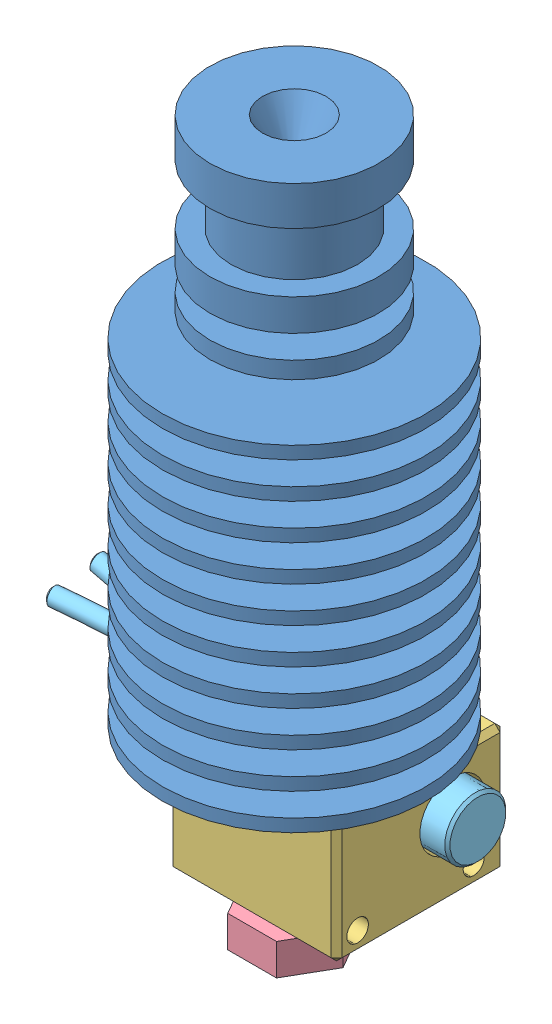
SolidWorks assembly E3D Hot End, configuration Default. Lengths in mm.
Overall size (41.43 69.7 25).
5 component instances, 5 part files, 13 mates.
Components (placement in the parent):
- Heat Sink^E3D Hot End-1: Heat Sink^E3D Hot End [Default] at (0 50.1 0) x (-1 0 0) z (0 0 1) size (25 50.1 25) (virtual)
- Heat Break^E3D Hot End-1: Heat Break^E3D Hot End [Default] at (0 18 0) x (-0.28377 0 0.958892) z (0.958892 0 0.28377) size (6 25.1 6) (virtual)
- Heater Block^E3D Hot End-1: Heater Block^E3D Hot End [Default] at (0 -7.85 -4) x (0 0 -1) z (1 0 0) size (16 12 16) (virtual)
- Nozzle^E3D Hot End-1: Nozzle^E3D Hot End [Default] at (0 -19.6 0) x (0.93034 0 0.366697) z (-0.366697 0 0.93034) size (8.59 12.5 9.14) (virtual)
- Heating Element^E3D Hot End-1: Heating Element^E3D Hot End [Default] at (-0.2277 -6.85 -7) x (1 0 0) z (0 0.127992 0.991775) size (39.33 5.8 6.45) (virtual)
Mates (geometry in assembly coordinates):
- Parallel1: parallel anti-aligned: plane of Heat Break^E3D Hot End-1 through (0 -7.1 0) normal (0 -1 0); plane of assembly through (0 0 0) normal (0 1 0)
- Coincident2: coincident: plane of Heat Sink^E3D Hot End-1 through (0 0 0) normal (0 -1 0); plane of assembly through (0 0 0) normal (0 1 0)
- Coincident3: coincident: plane of Heat Sink^E3D Hot End-1 through (0 50.1 0) normal (0 0 1); plane of assembly through (0 0 0) normal (0 0 1)
- Coincident4: coincident anti-aligned: plane of Heat Sink^E3D Hot End-1; plane of assembly through (0 0 0) normal (1 0 0)
- Concentric2: concentric aligned: cylinder of Heat Sink^E3D Hot End-1 through (0 0 0) axis (0 -1 0) radius 3; cylinder of Heat Break^E3D Hot End-1 through (0 -7.1 0) axis (0 -1 0) radius 3
- Coincident6: coincident anti-aligned: plane of Heat Sink^E3D Hot End-1 through (-1 18 0) normal (0 -1 0); plane of Heat Break^E3D Hot End-1 through (0 18 0) normal (0 1 0)
- Concentric3: concentric aligned: cylinder of Heat Break^E3D Hot End-1 through (0 -7.1 0) axis (0 -1 0) radius 3; cylinder of Heater Block^E3D Hot End-1 through (0 -1.85 0) axis (0 -1 0) radius 3
- Concentric4: concentric anti-aligned: cylinder of Heater Block^E3D Hot End-1 through (0 -1.85 0) axis (0 -1 0) radius 3; cylinder of Nozzle^E3D Hot End-1 through (0 -7.1 0) axis (0 1 0) radius 3
- Coincident7: coincident anti-aligned: plane of Heat Break^E3D Hot End-1 through (0 -7.1 0) normal (0 -1 0); plane of Nozzle^E3D Hot End-1 through (0 -7.1 0) normal (0 1 0)
- Tangent1: tangent: circle of Heat Break^E3D Hot End-1; circle of Heater Block^E3D Hot End-1
- Parallel2: parallel anti-aligned: plane of Heater Block^E3D Hot End-1 through (0 -7.85 -4) normal (0 0 -1); plane of assembly through (0 0 0) normal (0 0 1)
- Parallel3: parallel aligned: plane of Heater Block^E3D Hot End-1 through (0 -1.85 4) normal (0 0 1); plane of Nozzle^E3D Hot End-1 through (-2.3094 -24.6 4) normal (0 0 1)
- Concentric5: concentric anti-aligned: cylinder of Heater Block^E3D Hot End-1 through (-8 -6.85 -7) axis (1 0 0) radius 3.1; cylinder of Heating Element^E3D Hot End-1 through (10.3973 -6.85 -7) axis (-1 0 0) radius 2.9
